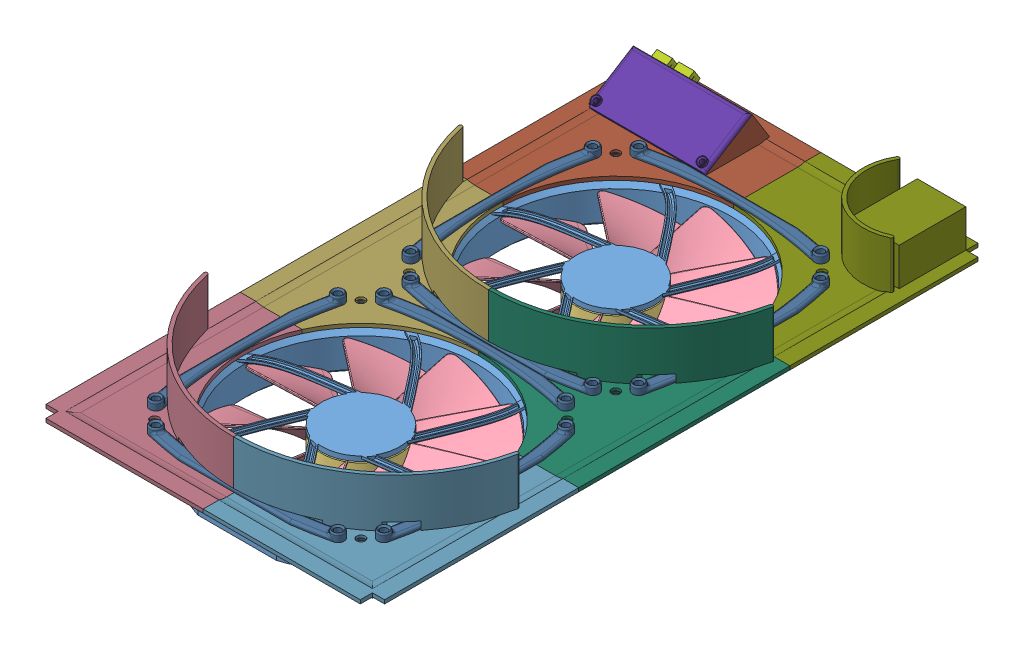
SolidWorks assembly Fan-Holder-Top, configuration Standard. Lengths in mm.
Overall size (279 74.13 511.33).
69 component instances, 17 part files, 118 mates.
Components (placement in the parent):
- NF-A20-1: NF-A20 [Standard] at (37.5 -31 481) x (-1 0 0) z (0 0 1) size (257.72 31.13 257.72)
  - NF-A20-Caase-1: NF-A20-Caase [Standard] at origin size (204 31 204)
    - NF-A20-Case-1: NF-A20-Case [Standard] at (-102 -30.5 -102) size (204 30 204)
    - NF-A20-Rubber-Edge-1: NF-A20-Rubber-Edge [Standard] at (-101.5 -0.5 -101.5) x (0 0 1) z (1 0 0) size (33.51 6.5 33.5)
    - NF-A20-Rubber-Edge-2: NF-A20-Rubber-Edge [Standard] at (-101.5 -0.5 -102.5) x (1 0 0) z (0 0 -1) size (33.51 6.5 33.5)
    - NF-A20-Rubber-Edge-3: NF-A20-Rubber-Edge [Standard] at (-102.5 -0.5 -101.5) x (-1 0 0) z (0 0 1) size (33.51 6.5 33.5)
    - NF-A20-Rubber-Edge-4: NF-A20-Rubber-Edge [Standard] at (-102.5 -0.5 -102.5) x (0 0 -1) z (-1 0 0) size (33.51 6.5 33.5)
    - NF-A20-Rubber-Edge-5: NF-A20-Rubber-Edge [Standard] at (-102.5 -30.5 -102.5) x (-1 0 0) z (0 0 -1) size (33.51 6.5 33.5)
    - NF-A20-Rubber-Edge-6: NF-A20-Rubber-Edge [Standard] at (-101.5 -30.5 -102.5) x (0 0 -1) z (1 0 0) size (33.51 6.5 33.5)
    - NF-A20-Rubber-Edge-7: NF-A20-Rubber-Edge [Standard] at (-102.5 -30.5 -101.5) x (0 0 1) z (-1 0 0) size (33.51 6.5 33.5)
    - NF-A20-Rubber-Edge-8: NF-A20-Rubber-Edge [Standard] at (-101.5 -30.5 -101.5) size (33.51 6.5 33.5)
  - NF-A20-Rotor-1: NF-A20-Rotor [Standard] at (-56.8129 -0.5 -99.5251) x (0.667379 0 0.744718) z (-0.744718 0 0.667379) size (214.05 28.34 214.61)
    - NF-A20-Rotor-Core-1: NF-A20-Rotor-Core [Standard] at (-32 -30 32) x (0.999376 0 -0.035329) z (0.035329 0 0.999376) size (64 25 64)
    - NF-A20-Rotor-Fin-1: NF-A20-Rotor-Fin [Standard] at (-33.0712 -30.212 32.0423) x (0.970961 -0.007209 0.239128) z (-0.23919 -0.009447 0.970927) size (68.87 27.34 53.71)
    - NF-A20-Rotor-Fin-2: NF-A20-Rotor-Fin [Standard] at (-32.8478 -30.212 31.3438) x (0.590091 -0.007209 0.807305) z (-0.80733 -0.009447 0.590025) size (68.87 27.34 53.71)
    - NF-A20-Rotor-Fin-3: NF-A20-Rotor-Fin [Standard] at (-32.2277 -30.212 30.9524) x (-0.06689 -0.007209 0.997734) z (-0.997711 -0.009447 -0.066957) size (68.87 27.34 53.71)
    - NF-A20-Rotor-Fin-4: NF-A20-Rotor-Fin [Standard] at (-31.501 -30.212 31.0512) x (-0.692572 -0.007209 0.721313) z (-0.721252 -0.009447 -0.692608) size (68.87 27.34 53.71)
    - NF-A20-Rotor-Fin-5: NF-A20-Rotor-Fin [Standard] at (-31.0079 -30.212 31.5939) x (-0.994192 -0.007209 0.107381) z (-0.107311 -0.009447 -0.994181) size (68.87 27.34 53.71)
    - NF-A20-Rotor-Fin-6: NF-A20-Rotor-Fin [Standard] at (-30.9789 -30.212 32.3266) x (-0.830618 -0.007209 -0.556796) z (0.556842 -0.009447 -0.830565) size (68.87 27.34 53.71)
    - NF-A20-Rotor-Fin-7: NF-A20-Rotor-Fin [Standard] at (-31.4278 -30.212 32.9066) x (-0.278389 -0.007209 -0.960441) z (0.960442 -0.009447 -0.278319) size (68.87 27.34 53.71)
    - NF-A20-Rotor-Fin-8: NF-A20-Rotor-Fin [Standard] at (-32.1444 -30.212 33.0623) x (0.404101 -0.007209 -0.914686) z (0.914641 -0.009447 0.404156) size (68.87 27.34 53.71)
    - NF-A20-Rotor-Fin-9: NF-A20-Rotor-Fin [Standard] at (-32.7934 -30.212 32.7209) x (0.897508 -0.007209 -0.440939) z (0.440869 -0.009447 0.897522) size (68.87 27.34 53.71)
- NF-A20-2: NF-A20 [Standard] at (37.5 -31 271) x (-1 0 0) z (0 0 1) size (257.72 31.13 257.72)
  - NF-A20-Caase-1: NF-A20-Caase [Standard] at origin size (204 31 204)
    - NF-A20-Case-1: NF-A20-Case [Standard] at (-102 -30.5 -102) size (204 30 204)
    - NF-A20-Rubber-Edge-1: NF-A20-Rubber-Edge [Standard] at (-101.5 -0.5 -101.5) x (0 0 1) z (1 0 0) size (33.51 6.5 33.5)
    - NF-A20-Rubber-Edge-2: NF-A20-Rubber-Edge [Standard] at (-101.5 -0.5 -102.5) x (1 0 0) z (0 0 -1) size (33.51 6.5 33.5)
    - NF-A20-Rubber-Edge-3: NF-A20-Rubber-Edge [Standard] at (-102.5 -0.5 -101.5) x (-1 0 0) z (0 0 1) size (33.51 6.5 33.5)
    - NF-A20-Rubber-Edge-4: NF-A20-Rubber-Edge [Standard] at (-102.5 -0.5 -102.5) x (0 0 -1) z (-1 0 0) size (33.51 6.5 33.5)
    - NF-A20-Rubber-Edge-5: NF-A20-Rubber-Edge [Standard] at (-102.5 -30.5 -102.5) x (-1 0 0) z (0 0 -1) size (33.51 6.5 33.5)
    - NF-A20-Rubber-Edge-6: NF-A20-Rubber-Edge [Standard] at (-101.5 -30.5 -102.5) x (0 0 -1) z (1 0 0) size (33.51 6.5 33.5)
    - NF-A20-Rubber-Edge-7: NF-A20-Rubber-Edge [Standard] at (-102.5 -30.5 -101.5) x (0 0 1) z (-1 0 0) size (33.51 6.5 33.5)
    - NF-A20-Rubber-Edge-8: NF-A20-Rubber-Edge [Standard] at (-101.5 -30.5 -101.5) size (33.51 6.5 33.5)
  - NF-A20-Rotor-1: NF-A20-Rotor [Standard] at (-56.8129 -0.5 -99.5251) x (0.667379 0 0.744718) z (-0.744718 0 0.667379) size (214.05 28.34 214.61)
    - NF-A20-Rotor-Core-1: NF-A20-Rotor-Core [Standard] at (-32 -30 32) x (0.999376 0 -0.035329) z (0.035329 0 0.999376) size (64 25 64)
    - NF-A20-Rotor-Fin-1: NF-A20-Rotor-Fin [Standard] at (-33.0712 -30.212 32.0423) x (0.970961 -0.007209 0.239128) z (-0.23919 -0.009447 0.970927) size (68.87 27.34 53.71)
    - NF-A20-Rotor-Fin-2: NF-A20-Rotor-Fin [Standard] at (-32.8478 -30.212 31.3438) x (0.590091 -0.007209 0.807305) z (-0.80733 -0.009447 0.590025) size (68.87 27.34 53.71)
    - NF-A20-Rotor-Fin-3: NF-A20-Rotor-Fin [Standard] at (-32.2277 -30.212 30.9524) x (-0.06689 -0.007209 0.997734) z (-0.997711 -0.009447 -0.066957) size (68.87 27.34 53.71)
    - NF-A20-Rotor-Fin-4: NF-A20-Rotor-Fin [Standard] at (-31.501 -30.212 31.0512) x (-0.692572 -0.007209 0.721313) z (-0.721252 -0.009447 -0.692608) size (68.87 27.34 53.71)
    - NF-A20-Rotor-Fin-5: NF-A20-Rotor-Fin [Standard] at (-31.0079 -30.212 31.5939) x (-0.994192 -0.007209 0.107381) z (-0.107311 -0.009447 -0.994181) size (68.87 27.34 53.71)
    - NF-A20-Rotor-Fin-6: NF-A20-Rotor-Fin [Standard] at (-30.9789 -30.212 32.3266) x (-0.830618 -0.007209 -0.556796) z (0.556842 -0.009447 -0.830565) size (68.87 27.34 53.71)
    - NF-A20-Rotor-Fin-7: NF-A20-Rotor-Fin [Standard] at (-31.4278 -30.212 32.9066) x (-0.278389 -0.007209 -0.960441) z (0.960442 -0.009447 -0.278319) size (68.87 27.34 53.71)
    - NF-A20-Rotor-Fin-8: NF-A20-Rotor-Fin [Standard] at (-32.1444 -30.212 33.0623) x (0.404101 -0.007209 -0.914686) z (0.914641 -0.009447 0.404156) size (68.87 27.34 53.71)
    - NF-A20-Rotor-Fin-9: NF-A20-Rotor-Fin [Standard] at (-32.7934 -30.212 32.7209) x (0.897508 -0.007209 -0.440939) z (0.440869 -0.009447 0.897522) size (68.87 27.34 53.71)
- C13-1: C13 [Standard] at (428.85 142.117 11.7209) x (0 0.66262 0.748956) z (0 -0.748956 0.66262) size (33.71 31.21 34)
- Keystone-LC-1: Keystone-LC [Standard] at (15.4 21.5546 20.9693) x (-1 0 0) z (0 0.529919 -0.848048) size (22 18.2 25.8)
  - Keystone-LC-Pannel-1: Keystone-LC-Pannel [Standard] at (-14.6 -17.2 0) x (-1 0 0) z (0 0 -1) size (14.6 18.2 2)
  - CONN-LC-TYPE-SCREW-1: CONN-LC-TYPE-SCREW [Standard] at (-7.3 -13.7 7.9) size (22 9.3 25.8)
- Keystone-LC-2: Keystone-LC [Standard] at (33.4 21.5546 20.9693) x (-1 0 0) z (0 0.529919 -0.848048) size (22 18.2 25.8)
  - Keystone-LC-Pannel-1: Keystone-LC-Pannel [Standard] at (-14.6 -17.2 0) x (-1 0 0) z (0 0 -1) size (14.6 18.2 2)
  - CONN-LC-TYPE-SCREW-1: CONN-LC-TYPE-SCREW [Standard] at (-7.3 -13.7 7.9) size (22 9.3 25.8)
- Keystone-Blind-1: Keystone-Blind [Standard] at (66 6.9682 11.8547) x (1 0 0) z (0 -0.529919 0.848048) size (14.6 18.2 2)
- Keystone-Blind-2: Keystone-Blind [Standard] at (84 6.9682 11.8547) x (1 0 0) z (0 -0.529919 0.848048) size (14.6 18.2 2)
- 1654552-1: 1654552 [Default] at (87.445 34.3463 17.1707) x (0 -0.529919 0.848048) z (1 0 0) size (27.46 23.5 18.55)
- Zusammenfügen-1: Zusammenfügen [Standard] at (64.5 3 285.0585) x (0 0 1) z (-1 0 0) size (15.62 6.5 160)
- Zusammenfügen-2: Zusammenfügen [Standard] at (214.5 3 262.9415) x (0 0 -1) z (1 0 0) size (15.62 6.5 160)
- Zusammenfügen-3: Zusammenfügen [Standard] at (45.5585 3 454) size (15.62 6.5 160)
- Zusammenfügen-4: Zusammenfügen [Standard] at (214.5 3 472.9415) x (0 0 -1) z (1 0 0) size (15.62 6.5 160)
- Zusammenfügen-5: Zusammenfügen [Standard] at (233.4415 3 304) x (-1 0 0) z (0 0 -1) size (15.62 6.5 160)
- Zusammenfügen-6: Zusammenfügen [Standard] at (233.4415 3 94) x (-1 0 0) z (0 0 -1) size (15.62 6.5 160)
- Zusammenfügen-7: Zusammenfügen [Standard] at (64.5 3 75.0585) x (0 0 1) z (-1 0 0) size (15.62 6.5 160)
- Zusammenfügen-8: Zusammenfügen [Standard] at (45.5585 3 244) size (15.62 6.5 160)
- Fan-Holder-Top-Part1-1: Fan-Holder-Top-Part1 [Standard] at (269 0 499) size (139.5 27.07 165)
- Fan-Holder-Top-Part2-1: Fan-Holder-Top-Part2 [Standard] at (269 0 499) size (139.5 43 174)
- Fan-Holder-Top-Part3-1: Fan-Holder-Top-Part3 [Standard] at (269 0 499) size (139.5 43 170)
- Fan-Holder-Top-Part4-1: Fan-Holder-Top-Part4 [Standard] at (269 0 499) size (139.5 43 170)
- Fan-Holder-Top-Part5-1: Fan-Holder-Top-Part5 [Standard] at (269 0 499) size (139.5 43 174)
- Fan-Holder-Top-Part6-1: Fan-Holder-Top-Part6 [Standard] at (269 0 499) size (139.5 43 165)
- Deckel-KEystone-1: Deckel-KEystone [Standard] at (107.4 3.0021 62.9255) x (0 -0.529919 0.848048) z (0 0.848048 0.529919) size (45.42 97.4 5.55)
Mates (geometry in assembly coordinates):
- Deckungsgleich1: coincident anti-aligned: plane of ? through (73.7611 18.7164 245) normal (0 -1 0); plane of NF-A20-1/NF-A20-Caase-1/NF-A20-Rubber-Edge-2 through (24.0083 18.7164 204.75) normal (0 1 0)
- Deckungsgleich2: coincident anti-aligned: plane of ? through (73.7611 18.7164 245) normal (0 -1 0); plane of NF-A20-2/NF-A20-Caase-1/NF-A20-Rubber-Edge-2 through (24.0083 18.7164 -5.25) normal (0 1 0)
- Konzentrisch1: concentric aligned: cylinder of ? through (29.2611 21.7164 210) axis (0 -1 0) radius 2.75; cylinder of NF-A20-1/NF-A20-Caase-1/NF-A20-Case-1 through (29.2611 18.2164 210) axis (0 -1 0) radius 3
- Konzentrisch2: concentric aligned: cylinder of ? through (-140.7389 21.7164 40) axis (0 -1 0) radius 2.75; cylinder of NF-A20-1/NF-A20-Caase-1/NF-A20-Case-1 through (-140.7389 18.2164 40) axis (0 -1 0) radius 3
- Konzentrisch3: concentric aligned: cylinder of ? through (29.2611 21.7164 0) axis (0 -1 0) radius 2.75; cylinder of NF-A20-2/NF-A20-Caase-1/NF-A20-Case-1 through (29.2611 18.2164 0) axis (0 -1 0) radius 3
- Konzentrisch4: concentric aligned: cylinder of ? through (-140.7389 21.7164 -170) axis (0 -1 0) radius 2.75; cylinder of NF-A20-2/NF-A20-Caase-1/NF-A20-Case-1 through (-140.7389 18.2164 -170) axis (0 -1 0) radius 3
- Deckungsgleich4: coincident anti-aligned: plane of ? through (68.7611 25.2164 -242) normal (0 0 -1); plane of C13-1 through (53.7611 36.7164 -242) normal (0 0 1)
- Breite1: width anti-aligned: plane of C13-1 through (40.5111 34.5221 -242) normal (-1 0 0); plane of C13-1 through (67.0111 41.9664 -242) normal (1 0 0); plane of ? through (39.9111 44.8164 -214) normal (1 0 0); plane of ? through (67.6111 44.8164 -214) normal (-1 0 0)
- Breite2: width aligned: plane of C13-1 through (39.7611 48.7164 -245) normal (0 1 0); plane of C13-1 through (67.7611 24.7164 -245) normal (0 -1 0); plane of ? through (65.6111 46.8164 -214) normal (0 -1 0); plane of ? through (65.6111 26.6164 -214) normal (0 1 0)
- Deckungsgleich5: coincident aligned: plane of ? through (-87.8389 22.7164 -244) normal (0 0.529919 -0.848048); plane of Keystone-LC-1/Keystone-LC-Pannel-1 through (-165.2389 25.6846 -242.1453) normal (0 0.529919 -0.848048)
- Deckungsgleich6: coincident aligned: plane of ? through (-87.8389 22.7164 -244) normal (0 0.529919 -0.848048); plane of ? through (-147.2389 25.6846 -242.1453) normal (0 0.529919 -0.848048)
- Deckungsgleich7: coincident aligned: plane of ? through (-87.8389 22.7164 -244) normal (0 0.529919 -0.848048); plane of Keystone-Blind-1 through (-129.2389 25.6846 -242.1453) normal (0 0.529919 -0.848048)
- Deckungsgleich8: coincident aligned: plane of ? through (-87.8389 22.7164 -244) normal (0 0.529919 -0.848048); plane of Keystone-Blind-2 through (-111.2389 25.6846 -242.1453) normal (0 0.529919 -0.848048)
- Breite3: width aligned: plane of ? through (-179.8389 25.1546 -241.2972) normal (-1 0 0); plane of ? through (-165.2389 25.1546 -241.2972) normal (1 0 0); plane of ? through (-164.8389 27.1289 -212.9425) normal (-1 0 0); plane of ? through (-180.2389 27.1289 -212.9425) normal (1 0 0)
- Breite4: width aligned: plane of ? through (-147.2389 25.1546 -241.2972) normal (1 0 0); plane of ? through (-161.8389 25.1546 -241.2972) normal (-1 0 0); plane of ? through (-162.2389 27.1289 -212.9425) normal (1 0 0); plane of ? through (-146.8389 27.1289 -212.9425) normal (-1 0 0)
- Breite5: width anti-aligned: plane of ? through (-143.8389 25.1546 -241.2972) normal (-1 0 0); plane of ? through (-129.2389 25.1546 -241.2972) normal (1 0 0); plane of ? through (-144.2389 27.1289 -212.9425) normal (1 0 0); plane of ? through (-128.8389 27.1289 -212.9425) normal (-1 0 0)
- Breite6: width anti-aligned: plane of ? through (-125.8389 25.1546 -241.2972) normal (-1 0 0); plane of ? through (-111.2389 25.1546 -241.2972) normal (1 0 0); plane of ? through (-126.2389 27.1289 -212.9425) normal (1 0 0); plane of ? through (-110.8389 27.1289 -212.9425) normal (-1 0 0)
- Breite7: width aligned: plane of ? through (-129.2389 38.893 -232.7125) normal (0 0.848048 0.529919); plane of ? through (-129.2389 25.1546 -241.2972) normal (0 -0.848048 -0.529919); plane of ? through (-180.2389 12.5425 -222.0571) normal (0 0.848048 0.529919); plane of ? through (-144.2389 27.1289 -212.9425) normal (0 -0.848048 -0.529919)
- Breite8: width aligned: plane of ? through (-111.2389 38.893 -232.7125) normal (0 0.848048 0.529919); plane of ? through (-111.2389 25.1546 -241.2972) normal (0 -0.848048 -0.529919); plane of ? through (-180.2389 12.5425 -222.0571) normal (0 0.848048 0.529919); plane of ? through (-126.2389 27.1289 -212.9425) normal (0 -0.848048 -0.529919)
- Breite9: width aligned: plane of ? through (-147.2389 25.1546 -241.2972) normal (0 -0.848048 -0.529919); plane of ? through (-147.2389 38.893 -232.7125) normal (0 0.848048 0.529919); plane of ? through (-162.2389 27.1289 -212.9425) normal (0 -0.848048 -0.529919); plane of ? through (-180.2389 12.5425 -222.0571) normal (0 0.848048 0.529919)
- Breite10: width aligned: plane of ? through (-165.2389 25.1546 -241.2972) normal (0 -0.848048 -0.529919); plane of ? through (-165.2389 38.893 -232.7125) normal (0 0.848048 0.529919); plane of ? through (-180.2389 27.1289 -212.9425) normal (0 -0.848048 -0.529919); plane of ? through (-180.2389 12.5425 -222.0571) normal (0 0.848048 0.529919)
- Deckungsgleich9: coincident anti-aligned: plane of ? through (73.7611 21.7164 245) normal (0 1 0); plane of Zusammenfügen-1 through (-55.7389 21.7164 352.4228) normal (0 -1 0)
- Deckungsgleich10: coincident anti-aligned: plane of ? through (73.7611 21.7164 245) normal (0 1 0); plane of Zusammenfügen-2 through (-55.7389 21.7164 -312.4228) normal (0 -1 0)
- Konzentrisch5: concentric aligned: cylinder of ? through (-130.7389 21.7164 8.9415) axis (0 -1 0) radius 2; cylinder of Zusammenfügen-2 through (-130.7389 24.7164 8.9415) axis (0 -1 0) radius 3
- Konzentrisch6: concentric aligned: cylinder of ? through (19.2611 21.7164 8.9415) axis (0 -1 0) radius 2; cylinder of Zusammenfügen-2 through (19.2611 24.7164 8.9415) axis (0 -1 0) radius 3
- Konzentrisch7: concentric aligned: cylinder of ? through (19.2611 21.7164 31.0585) axis (0 -1 0) radius 2; cylinder of Zusammenfügen-1 through (19.2611 24.7164 31.0585) axis (0 -1 0) radius 3
- Konzentrisch8: concentric aligned: cylinder of ? through (-130.7389 21.7164 31.0585) axis (0 -1 0) radius 2; cylinder of Zusammenfügen-1 through (-130.7389 24.7164 31.0585) axis (0 -1 0) radius 3
- Deckungsgleich11: coincident anti-aligned: plane of ? through (73.7611 21.7164 245) normal (0 1 0); plane of Zusammenfügen-3 through (171.6839 21.7164 125) normal (0 -1 0)
- Deckungsgleich12: coincident anti-aligned: plane of ? through (73.7611 21.7164 245) normal (0 1 0); plane of Zusammenfügen-4 through (-55.7389 21.7164 -102.4228) normal (0 -1 0)
- Deckungsgleich13: coincident anti-aligned: plane of ? through (73.7611 21.7164 245) normal (0 1 0); plane of Zusammenfügen-5 through (-283.1617 21.7164 125) normal (0 -1 0)
- Deckungsgleich14: coincident anti-aligned: plane of ? through (73.7611 21.7164 245) normal (0 1 0); plane of Zusammenfügen-6 through (-283.1617 21.7164 -85) normal (0 -1 0)
- Deckungsgleich15: coincident anti-aligned: plane of ? through (73.7611 21.7164 245) normal (0 1 0); plane of Zusammenfügen-7 through (-55.7389 21.7164 142.4228) normal (0 -1 0)
- Deckungsgleich16: coincident anti-aligned: plane of ? through (73.7611 21.7164 245) normal (0 1 0); plane of Zusammenfügen-8 through (171.6839 21.7164 -85) normal (0 -1 0)
- Konzentrisch9: concentric aligned: cylinder of ? through (-149.6804 21.7164 50) axis (0 -1 0) radius 2; cylinder of Zusammenfügen-3 through (-149.6804 24.7164 50) axis (0 -1 0) radius 3
- Konzentrisch10: concentric aligned: cylinder of ? through (-149.6804 21.7164 200) axis (0 -1 0) radius 2; cylinder of Zusammenfügen-3 through (-149.6804 24.7164 200) axis (0 -1 0) radius 3
- Konzentrisch11: concentric aligned: cylinder of ? through (-130.7389 21.7164 218.9415) axis (0 -1 0) radius 2; cylinder of Zusammenfügen-4 through (-130.7389 24.7164 218.9415) axis (0 -1 0) radius 3
- Konzentrisch12: concentric aligned: cylinder of ? through (19.2611 21.7164 218.9415) axis (0 -1 0) radius 2; cylinder of Zusammenfügen-4 through (19.2611 24.7164 218.9415) axis (0 -1 0) radius 3
- Konzentrisch13: concentric aligned: cylinder of ? through (38.2026 21.7164 200) axis (0 -1 0) radius 2; cylinder of Zusammenfügen-5 through (38.2026 24.7164 200) axis (0 -1 0) radius 3
- Konzentrisch14: concentric aligned: cylinder of ? through (38.2026 21.7164 50) axis (0 -1 0) radius 2; cylinder of Zusammenfügen-5 through (38.2026 24.7164 50) axis (0 -1 0) radius 3
- Konzentrisch15: concentric aligned: cylinder of ? through (38.2026 21.7164 -10) axis (0 -1 0) radius 2; cylinder of Zusammenfügen-6 through (38.2026 24.7164 -10) axis (0 -1 0) radius 3
- Konzentrisch16: concentric aligned: cylinder of ? through (38.2026 21.7164 -160) axis (0 -1 0) radius 2; cylinder of Zusammenfügen-6 through (38.2026 24.7164 -160) axis (0 -1 0) radius 3
- Konzentrisch17: concentric aligned: cylinder of ? through (19.2611 21.7164 -178.9415) axis (0 -1 0) radius 2; cylinder of Zusammenfügen-7 through (19.2611 24.7164 -178.9415) axis (0 -1 0) radius 3
- Konzentrisch18: concentric aligned: cylinder of ? through (-130.7389 21.7164 -178.9415) axis (0 -1 0) radius 2; cylinder of Zusammenfügen-7 through (-130.7389 24.7164 -178.9415) axis (0 -1 0) radius 3
- Konzentrisch19: concentric aligned: cylinder of ? through (-149.6804 21.7164 -160) axis (0 -1 0) radius 2; cylinder of Zusammenfügen-8 through (-149.6804 24.7164 -160) axis (0 -1 0) radius 3
- Konzentrisch20: concentric aligned: cylinder of ? through (-149.6804 21.7164 -10) axis (0 -1 0) radius 2; cylinder of Zusammenfügen-8 through (-149.6804 24.7164 -10) axis (0 -1 0) radius 3
- Deckungsgleich17: coincident aligned: plane of ? through (-87.8389 22.7164 -244) normal (0 0.529919 -0.848048); plane of 1654552-1 through (-93.2939 39.283 -233.648) normal (0 0.529919 -0.848048)
- Parallel1: parallel anti-aligned: plane of ? through (-180.2389 12.5425 -222.0571) normal (0 0.848048 0.529919); plane of 1654552-1 through (-107.7839 19.1326 -231.594) normal (0 -0.848048 -0.529919)
- Breite12: width anti-aligned: plane of ? through (-180.2389 12.5425 -222.0571) normal (0 0.848048 0.529919); plane of ? through (-108.2389 27.1289 -212.9425) normal (0 -0.848048 -0.529919); plane of 1654552-1 through (-107.7839 19.1326 -231.594) normal (0 -0.848048 -0.529919); plane of 1654552-1 through (-107.7839 34.1365 -225.1665) normal (0 0.848048 0.529919)
- Breite13: width aligned: plane of 1654552-1 through (-107.7839 4.1208 -210.7403) normal (-1 0 0); plane of 1654552-1 through (-93.2939 24.5499 -224.2233) normal (1 0 0); plane of ? through (-92.8389 27.1289 -212.9425) normal (-1 0 0); plane of ? through (-108.2389 27.1289 -212.9425) normal (1 0 0)
- Deckungsgleich18: coincident anti-aligned: plane of Fan-Holder-Top-Part1-1 through (269 0 499) normal (0 -1 0); plane of assembly through (0 0 0) normal (0 1 0)
- Deckungsgleich19: coincident anti-aligned: plane of Fan-Holder-Top-Part1-1 through (269 1 0) normal (0 0 -1); plane of assembly through (0 0 0) normal (0 0 1)
- Deckungsgleich20: coincident anti-aligned: plane of Fan-Holder-Top-Part1-1 through (0 1 499) normal (-1 0 0); plane of assembly through (0 0 0) normal (1 0 0)
- Deckungsgleich21: coincident: plane of NF-A20-2/NF-A20-Caase-1/NF-A20-Rubber-Edge-3 through (59.7528 0 89.25) normal (0 1 0); plane of Fan-Holder-Top-Part1-1 through (269 0 499) normal (0 -1 0)
- Konzentrisch21: concentric: cylinder of NF-A20-2/NF-A20-Caase-1/NF-A20-Case-1 through (54.5 -0.5 84) axis (0 -1 0) radius 3; cylinder of Fan-Holder-Top-Part1-1 through (54.5 3 84) axis (0 -1 0) radius 2.75
- Deckungsgleich22: coincident anti-aligned: plane of Zusammenfügen-8 through (366.9228 3 169) normal (0 -1 0); plane of Fan-Holder-Top-Part1-1 through (269 3 499) normal (0 1 0)
- Konzentrisch22: concentric aligned: cylinder of Zusammenfügen-8 through (45.5585 6 94) axis (0 -1 0) radius 3; cylinder of Fan-Holder-Top-Part1-1 through (45.5585 3 94) axis (0 -1 0) radius 2
- Deckungsgleich23: coincident: plane of Zusammenfügen-7 through (139.5 3 396.4228) normal (0 -1 0); plane of Fan-Holder-Top-Part1-1 through (269 3 499) normal (0 1 0)
- Konzentrisch23: concentric: cylinder of Zusammenfügen-7 through (64.5 6 75.0585) axis (0 -1 0) radius 3; cylinder of Fan-Holder-Top-Part1-1 through (64.5 3 75.0585) axis (0 -1 0) radius 2
- Deckungsgleich24: coincident aligned: plane of Keystone-LC-1/Keystone-LC-Pannel-1 through (30 6.9682 11.8547) normal (0 0.529919 -0.848048); plane of Fan-Holder-Top-Part1-1 through (107.4 4 10) normal (0 0.529919 -0.848048)
- Deckungsgleich25: coincident aligned: plane of Keystone-LC-2/Keystone-LC-Pannel-1 through (48 6.9682 11.8547) normal (0 0.529919 -0.848048); plane of Fan-Holder-Top-Part1-1 through (107.4 4 10) normal (0 0.529919 -0.848048)
- Deckungsgleich26: coincident aligned: plane of Keystone-Blind-1 through (66 6.9682 11.8547) normal (0 0.529919 -0.848048); plane of Fan-Holder-Top-Part1-1 through (107.4 4 10) normal (0 0.529919 -0.848048)
- Deckungsgleich27: coincident aligned: plane of Keystone-Blind-2 through (84 6.9682 11.8547) normal (0 0.529919 -0.848048); plane of Fan-Holder-Top-Part1-1 through (107.4 4 10) normal (0 0.529919 -0.848048)
- Deckungsgleich28: coincident aligned: plane of 1654552-1 through (101.945 20.5666 20.352) normal (0 0.529919 -0.848048); plane of Fan-Holder-Top-Part1-1 through (107.4 4 10) normal (0 0.529919 -0.848048)
- Breite14: width anti-aligned: plane of 1654552-1 through (101.945 5.8335 29.7767) normal (1 0 0); plane of 1654552-1 through (87.455 -14.5956 43.2597) normal (-1 0 0); plane of Fan-Holder-Top-Part1-1 through (102.4 8.4125 41.0575) normal (-1 0 0); plane of Fan-Holder-Top-Part1-1 through (87 8.4125 41.0575) normal (1 0 0)
- Breite15: width anti-aligned: plane of Keystone-Blind-2 through (84 6.4382 12.7028) normal (1 0 0); plane of Keystone-Blind-2 through (69.4 6.4382 12.7028) normal (-1 0 0); plane of Fan-Holder-Top-Part1-1 through (84.4 8.4125 41.0575) normal (-1 0 0); plane of Fan-Holder-Top-Part1-1 through (69 8.4125 41.0575) normal (1 0 0)
- Breite16: width anti-aligned: plane of Keystone-Blind-1 through (66 6.4382 12.7028) normal (1 0 0); plane of Keystone-Blind-1 through (51.4 6.4382 12.7028) normal (-1 0 0); plane of Fan-Holder-Top-Part1-1 through (66.4 8.4125 41.0575) normal (-1 0 0); plane of Fan-Holder-Top-Part1-1 through (51 8.4125 41.0575) normal (1 0 0)
- Breite17: width anti-aligned: plane of Keystone-LC-2/Keystone-LC-Pannel-1 through (48 6.4382 12.7028) normal (1 0 0); plane of Keystone-LC-2/Keystone-LC-Pannel-1 through (33.4 6.4382 12.7028) normal (-1 0 0); plane of Fan-Holder-Top-Part1-1 through (48.4 8.4125 41.0575) normal (-1 0 0); plane of Fan-Holder-Top-Part1-1 through (33 8.4125 41.0575) normal (1 0 0)
- Breite18: width anti-aligned: plane of Keystone-LC-1/Keystone-LC-Pannel-1 through (30 6.4382 12.7028) normal (1 0 0); plane of Keystone-LC-1/Keystone-LC-Pannel-1 through (15.4 6.4382 12.7028) normal (-1 0 0); plane of Fan-Holder-Top-Part1-1 through (30.4 8.4125 41.0575) normal (-1 0 0); plane of Fan-Holder-Top-Part1-1 through (15 8.4125 41.0575) normal (1 0 0)
- Breite19: width aligned: plane of 1654552-1 through (87.455 15.4201 28.8335) normal (0 0.848048 0.529919); plane of 1654552-1 through (87.455 0.4163 22.406) normal (0 -0.848048 -0.529919); plane of Fan-Holder-Top-Part1-1 through (15 -6.1739 31.9429) normal (0 0.848048 0.529919); plane of Fan-Holder-Top-Part1-1 through (87 8.4125 41.0575) normal (0 -0.848048 -0.529919)
- Breite20: width aligned: plane of Fan-Holder-Top-Part1-1 through (69 8.4125 41.0575) normal (0 -0.848048 -0.529919); plane of Fan-Holder-Top-Part1-1 through (15 -6.1739 31.9429) normal (0 0.848048 0.529919); plane of Keystone-Blind-2 through (84 6.4382 12.7028) normal (0 -0.848048 -0.529919); plane of Keystone-Blind-2 through (84 20.1766 21.2875) normal (0 0.848048 0.529919)
- Breite21: width anti-aligned: plane of Keystone-Blind-1 through (66 20.1766 21.2875) normal (0 0.848048 0.529919); plane of Keystone-Blind-1 through (66 6.4382 12.7028) normal (0 -0.848048 -0.529919); plane of Fan-Holder-Top-Part1-1 through (51 8.4125 41.0575) normal (0 -0.848048 -0.529919); plane of Fan-Holder-Top-Part1-1 through (15 -6.1739 31.9429) normal (0 0.848048 0.529919)
- Breite22: width anti-aligned: plane of Keystone-LC-2/Keystone-LC-Pannel-1 through (48 20.1766 21.2875) normal (0 0.848048 0.529919); plane of Keystone-LC-2/Keystone-LC-Pannel-1 through (48 6.4382 12.7028) normal (0 -0.848048 -0.529919); plane of Fan-Holder-Top-Part1-1 through (33 8.4125 41.0575) normal (0 -0.848048 -0.529919); plane of Fan-Holder-Top-Part1-1 through (15 -6.1739 31.9429) normal (0 0.848048 0.529919)
- Breite23: width anti-aligned: plane of Keystone-LC-1/Keystone-LC-Pannel-1 through (30 20.1766 21.2875) normal (0 0.848048 0.529919); plane of Keystone-LC-1/Keystone-LC-Pannel-1 through (30 6.4382 12.7028) normal (0 -0.848048 -0.529919); plane of Fan-Holder-Top-Part1-1 through (15 8.4125 41.0575) normal (0 -0.848048 -0.529919); plane of Fan-Holder-Top-Part1-1 through (15 -6.1739 31.9429) normal (0 0.848048 0.529919)
- Deckungsgleich29: coincident anti-aligned: plane of Fan-Holder-Top-Part1-1 through (269 0 165) normal (0 0 1); plane of Fan-Holder-Top-Part2-1 through (269 0 165) normal (0 0 -1)
- Deckungsgleich30: coincident aligned: plane of Fan-Holder-Top-Part1-1 through (269 3 499) normal (0 1 0); plane of Fan-Holder-Top-Part2-1 through (269 3 499) normal (0 1 0)
- Deckungsgleich31: coincident aligned: plane of Fan-Holder-Top-Part1-1 through (0 1 499) normal (-1 0 0); plane of Fan-Holder-Top-Part2-1 through (0 1 499) normal (-1 0 0)
- Konzentrisch24: concentric aligned: cylinder of Zusammenfügen-8 through (45.5585 6 244) axis (0 -1 0) radius 3; cylinder of Fan-Holder-Top-Part2-1 through (45.5585 3 244) axis (0 -1 0) radius 2
- Konzentrisch25: concentric aligned: cylinder of NF-A20-1/NF-A20-Caase-1/NF-A20-Case-1 through (54.5 -0.5 294) axis (0 -1 0) radius 3; cylinder of Fan-Holder-Top-Part2-1 through (54.5 3 294) axis (0 -1 0) radius 2.75
- Deckungsgleich32: coincident anti-aligned: plane of NF-A20-1/NF-A20-Caase-1/NF-A20-Rubber-Edge-3 through (59.7528 0 299.25) normal (0 1 0); plane of Fan-Holder-Top-Part2-1 through (269 0 499) normal (0 -1 0)
- Deckungsgleich33: coincident: plane of Zusammenfügen-2 through (139.5 3 -58.4228) normal (0 -1 0); plane of Fan-Holder-Top-Part2-1 through (269 3 499) normal (0 1 0)
- Deckungsgleich34: coincident: plane of Zusammenfügen-1 through (139.5 3 606.4228) normal (0 -1 0); plane of Fan-Holder-Top-Part2-1 through (269 3 499) normal (0 1 0)
- Deckungsgleich35: coincident anti-aligned: plane of Zusammenfügen-3 through (366.9228 3 379) normal (0 -1 0); plane of Fan-Holder-Top-Part2-1 through (269 3 499) normal (0 1 0)
- Konzentrisch26: concentric: cylinder of Zusammenfügen-1 through (64.5 6 285.0585) axis (0 -1 0) radius 3; cylinder of Fan-Holder-Top-Part2-1 through (64.5 3 285.0585) axis (0 -1 0) radius 2
- Konzentrisch27: concentric: cylinder of Zusammenfügen-2 through (64.5 6 262.9415) axis (0 -1 0) radius 3; cylinder of Fan-Holder-Top-Part2-1 through (64.5 3 262.9415) axis (0 -1 0) radius 2
- Konzentrisch28: concentric aligned: cylinder of Zusammenfügen-3 through (45.5585 6 304) axis (0 -1 0) radius 3; cylinder of Fan-Holder-Top-Part2-1 through (45.5585 3 304) axis (0 -1 0) radius 2
- Deckungsgleich36: coincident aligned: plane of Fan-Holder-Top-Part2-1 through (269 3 499) normal (0 1 0); plane of Fan-Holder-Top-Part3-1 through (269 3 499) normal (0 1 0)
- Deckungsgleich37: coincident anti-aligned: plane of Fan-Holder-Top-Part2-1 through (269 0 339) normal (0 0 1); plane of Fan-Holder-Top-Part3-1 through (269 0 339) normal (0 0 -1)
- Deckungsgleich38: coincident aligned: plane of Fan-Holder-Top-Part2-1 through (0 1 499) normal (-1 0 0); plane of Fan-Holder-Top-Part3-1 through (0 1 499) normal (-1 0 0)
- Konzentrisch29: concentric aligned: cylinder of Zusammenfügen-3 through (45.5585 6 454) axis (0 -1 0) radius 3; cylinder of Fan-Holder-Top-Part3-1 through (45.5585 3 454) axis (0 -1 0) radius 2
- Deckungsgleich39: coincident anti-aligned: plane of Zusammenfügen-4 through (139.5 3 151.5772) normal (0 -1 0); plane of Fan-Holder-Top-Part3-1 through (269 3 499) normal (0 1 0)
- Konzentrisch30: concentric aligned: cylinder of Zusammenfügen-4 through (64.5 6 472.9415) axis (0 -1 0) radius 3; cylinder of Fan-Holder-Top-Part3-1 through (64.5 3 472.9415) axis (0 -1 0) radius 2
- Deckungsgleich40: coincident anti-aligned: plane of Fan-Holder-Top-Part3-1 through (139.5 0 499) normal (1 0 0); plane of Fan-Holder-Top-Part4-1 through (139.5 0 499) normal (-1 0 0)
- Deckungsgleich41: coincident aligned: plane of Fan-Holder-Top-Part3-1 through (269 4 499) normal (0 1 0); plane of Fan-Holder-Top-Part4-1 through (269 4 499) normal (0 1 0)
- Deckungsgleich42: coincident aligned: plane of Fan-Holder-Top-Part3-1 through (269 1 509) normal (0 0 1); plane of Fan-Holder-Top-Part4-1 through (269 1 509) normal (0 0 1)
- Konzentrisch31: concentric aligned: cylinder of Zusammenfügen-4 through (214.5 6 472.9415) axis (0 -1 0) radius 3; cylinder of Fan-Holder-Top-Part4-1 through (214.5 3 472.9415) axis (0 -1 0) radius 2
- Konzentrisch32: concentric aligned: cylinder of NF-A20-1/NF-A20-Caase-1/NF-A20-Case-1 through (224.5 -0.5 464) axis (0 -1 0) radius 3; cylinder of Fan-Holder-Top-Part4-1 through (224.5 3 464) axis (0 -1 0) radius 2.75
- Konzentrisch33: concentric aligned: cylinder of Zusammenfügen-5 through (233.4415 6 454) axis (0 -1 0) radius 3; cylinder of Fan-Holder-Top-Part4-1 through (233.4415 3 454) axis (0 -1 0) radius 2
- Deckungsgleich43: coincident anti-aligned: plane of Zusammenfügen-5 through (-87.9228 3 379) normal (0 -1 0); plane of Fan-Holder-Top-Part4-1 through (269 3 499) normal (0 1 0)
- Deckungsgleich44: coincident anti-aligned: plane of Fan-Holder-Top-Part4-1 through (269 0 339) normal (0 0 -1); plane of Fan-Holder-Top-Part5-1 through (269 0 339) normal (0 0 1)
- Deckungsgleich45: coincident aligned: plane of Fan-Holder-Top-Part4-1 through (269 4 499) normal (0 1 0); plane of Fan-Holder-Top-Part5-1 through (269 4 499) normal (0 1 0)
- Deckungsgleich46: coincident aligned: plane of Fan-Holder-Top-Part4-1 through (279 1 499) normal (1 0 0); plane of Fan-Holder-Top-Part5-1 through (279 1 499) normal (1 0 0)
- Konzentrisch34: concentric aligned: cylinder of Zusammenfügen-5 through (233.4415 6 304) axis (0 -1 0) radius 3; cylinder of Fan-Holder-Top-Part5-1 through (233.4415 3 304) axis (0 -1 0) radius 2
- Konzentrisch35: concentric aligned: cylinder of Zusammenfügen-1 through (214.5 6 285.0585) axis (0 -1 0) radius 3; cylinder of Fan-Holder-Top-Part5-1 through (214.5 3 285.0585) axis (0 -1 0) radius 2
- Konzentrisch36: concentric aligned: cylinder of Zusammenfügen-2 through (214.5 6 262.9415) axis (0 -1 0) radius 3; cylinder of Fan-Holder-Top-Part5-1 through (214.5 3 262.9415) axis (0 -1 0) radius 2
- Konzentrisch37: concentric aligned: cylinder of NF-A20-2/NF-A20-Caase-1/NF-A20-Case-1 through (224.5 -0.5 254) axis (0 -1 0) radius 3; cylinder of Fan-Holder-Top-Part5-1 through (224.5 3 254) axis (0 -1 0) radius 2.75
- Deckungsgleich47: coincident: plane of Zusammenfügen-6 through (-87.9228 3 169) normal (0 -1 0); plane of Fan-Holder-Top-Part5-1 through (269 3 499) normal (0 1 0)
- Konzentrisch38: concentric: cylinder of Zusammenfügen-6 through (233.4415 6 244) axis (0 -1 0) radius 3; cylinder of Fan-Holder-Top-Part5-1 through (233.4415 3 244) axis (0 -1 0) radius 2
- Deckungsgleich48: coincident: plane of Fan-Holder-Top-Part5-1 through (279 1 499) normal (1 0 0); plane of Fan-Holder-Top-Part6-1 through (279 1 499) normal (1 0 0)
- Deckungsgleich49: coincident: plane of Fan-Holder-Top-Part5-1 through (269 0 165) normal (0 0 -1); plane of Fan-Holder-Top-Part6-1 through (269 0 165) normal (0 0 1)
- Deckungsgleich50: coincident aligned: plane of Fan-Holder-Top-Part5-1 through (269 4 499) normal (0 1 0); plane of Fan-Holder-Top-Part6-1 through (269 4 499) normal (0 1 0)
- Konzentrisch39: concentric aligned: cylinder of Zusammenfügen-7 through (214.5 6 75.0585) axis (0 -1 0) radius 3; cylinder of Fan-Holder-Top-Part6-1 through (214.5 3 75.0585) axis (0 -1 0) radius 2
- Konzentrisch40: concentric aligned: cylinder of Zusammenfügen-6 through (233.4415 6 94) axis (0 -1 0) radius 3; cylinder of Fan-Holder-Top-Part6-1 through (233.4415 3 94) axis (0 -1 0) radius 2
- Breite24: width: plane of C13-1 through (264.5 28.5 9) normal (1 0 0); plane of C13-1 through (233.5 7.5 9) normal (-1 0 0); plane of ? through (233 6.5 12) normal (1 0 0); plane of ? through (265 6.5 12) normal (-1 0 0)
- Breite25: width: plane of C13-1 through (235 30 9) normal (0 1 0); plane of C13-1 through (263 6 9) normal (0 -1 0); plane of ? through (264 30.5 12) normal (0 -1 0); plane of ? through (264 5.5 12) normal (0 1 0)
- Deckungsgleich51: coincident anti-aligned: plane of C13-1 through (249 18 12) normal (0 0 1); plane of Fan-Holder-Top-Part6-1 through (264 6.5 12) normal (0 0 -1)
- Deckungsgleich52: coincident: plane of Fan-Holder-Top-Part1-1 through (107.4 27.0669 24.4138) normal (0 0.848048 0.529919); plane of Deckel-KEystone-1 through (107.4 3.0021 62.9255) normal (0 -0.848048 -0.529919)
- Konzentrisch41: concentric: cylinder of Fan-Holder-Top-Part1-1 through (102.4 -2.744 53.2504) axis (0 0.848048 0.529919) radius 1.5; cylinder of Deckel-KEystone-1 through (102.4 8.2807 60.1393) axis (0 -0.848048 -0.529919) radius 2
- Konzentrisch42: concentric anti-aligned: cylinder of Fan-Holder-Top-Part1-1 through (15 -2.744 53.2504) axis (0 0.848048 0.529919) radius 1.5; cylinder of Deckel-KEystone-1 through (15 8.2807 60.1393) axis (0 -0.848048 -0.529919) radius 2
